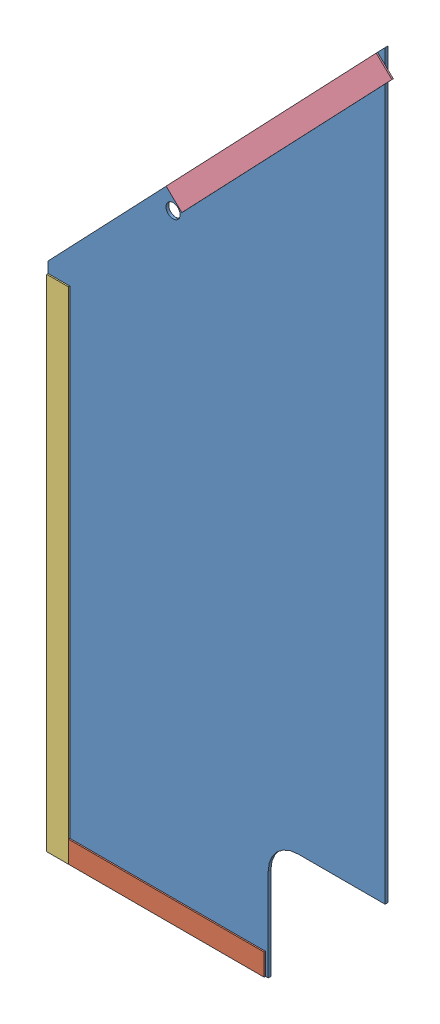
SolidWorks assembly GE-19088-Right-Assembly, configuration Right. Lengths in mm.
7 component instances, 4 part files, 9 mates.
Components (placement in the parent):
- GE-19088-1: GE-19088 [GE-19088] at origin
- Loop_1_9-1: Loop_1_9 [Default] at (-368.3 0 3.175) x (1 0 0) z (0 -1 0)
- Loop_1_23-1: Loop_1_23 [Default] at (-381 292.1 4.7625) x (0 -1 0) z (0 0 -1)
- Loop_1_14-3: Loop_1_14 [Default] at (-254.2047 743.1451 4.7625) x (0.690211 0.723608 0) z (-0.723608 0.690211 0)
- Loop_1_14-4: Loop_1_14 [Default] at (-235.825 725.6137 -1.5875) x (0.690211 0.723608 0) z (0.723608 -0.690211 0) (suppressed, hidden)
- Loop_1_23-2: Loop_1_23 [Default] at (-381 292.1 0) x (0 -1 0) z (0 0 -1) (suppressed, hidden)
- Loop_1_9-2: Loop_1_9 [Default] at (-368.3 25.4 0) x (1 0 0) z (0 1 0) (suppressed, hidden)
Mates (geometry in assembly coordinates):
- Coincident1: coincident: plane of assembly; plane of assembly; plane of GE-19088-1 through (0 0 3.175) normal (0 0 1); plane of Loop_1_23-1 through (-381 292.1 3.175) normal (0 0 -1)
- Coincident2: coincident: plane of assembly; plane of assembly; plane of GE-19088-1 through (-393.7 0 3.175) normal (-1 0 0); plane of Loop_1_23-1 through (-393.7 584.2 3.175) normal (-1 0 0)
- Coincident3: coincident: plane of assembly; plane of assembly; plane of GE-19088-1 through (0 0 3.175) normal (0 -1 0); plane of Loop_1_23-1 through (-393.7 0 3.175) normal (0 -1 0)
- Coincident4: coincident: plane of assembly; plane of assembly; plane of GE-19088-1 through (0 0 3.175) normal (0 0 1); plane of Loop_1_9-1 through (-368.3 0 3.175) normal (0 0 -1)
- Coincident5: coincident: plane of assembly; plane of assembly; plane of GE-19088-1 through (0 0 3.175) normal (0 -1 0); plane of Loop_1_9-1 through (-368.3 0 4.7625) normal (0 -1 0)
- Coincident6: coincident: plane of assembly; plane of assembly; plane of Loop_1_9-1 through (-368.3 0 4.7625) normal (-1 0 0); plane of Loop_1_23-1 through (-368.3 584.2 3.175) normal (1 0 0)
- Coincident10: coincident: plane of assembly; plane of assembly; plane of GE-19088-1 through (0 0 3.175) normal (0 0 1); plane of Loop_1_14-3 through (-254.2047 743.1451 3.175) normal (0 0 -1)
- Coincident11: coincident: plane of assembly; plane of assembly; plane of GE-19088-1 through (-393.7 596.9 3.175) normal (-0.723608 0.690211 0); plane of Loop_1_14-3 through (-254.2047 743.1451 3.175) normal (-0.723608 0.690211 0)
- Distance1: distance = 12.7 mm: plane of assembly; line of assembly; plane of Loop_1_14-3 through (-8.7657 1000.4602 3.175) normal (0.690211 0.723608 0); line of GE-19088-1 through (0 1009.65 3.175) axis (0 0 -1)
